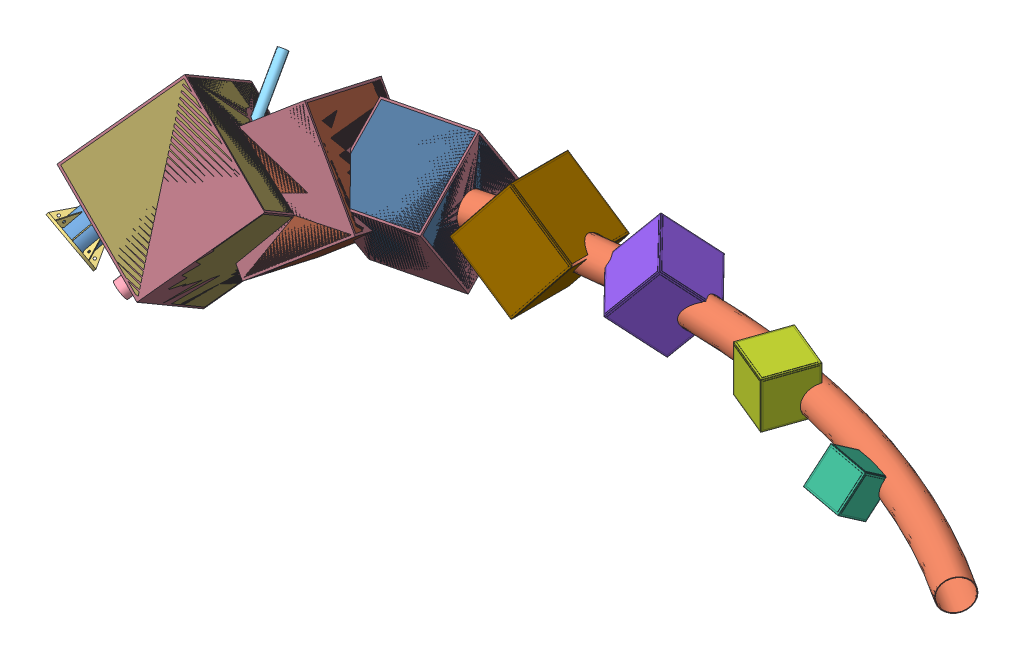
SolidWorks assembly tube1A, configuration Default. Lengths in mm.
Overall size (5509.57 1076.56 3983.87).
16 component instances, 13 part files, 11 mates.
Components (placement in the parent):
- tube1^tube1A-1: tube1^tube1A [A] at origin size (5509.57 567.54 3868.09) (virtual)
  - short-tube^tube1_tube1A-1: short-tube^tube1_tube1A [Default<As Machined>] at (-2066.9857 0 -335.3072) x (0.280011 0.524542 -0.804021) z (0.396988 0.699289 0.594471) size (592.32 168.28 168.28) (virtual)
  - tubes-1: tubes [tube1A] at origin size (5509.57 179.56 3868.09)
  - pipe_flange-1: pipe_flange [Default] at (-2222.5526 -291.4219 111.3861) x (0.228255 0.777129 0.58649) z (0.280011 0.524542 -0.804021) size (279.4 279.4 111.05)
-  tube1-support-arm^tube1A-1:  tube1-support-arm^tube1A [Default] at (-1841.3383 3296.5765 733.9451) x (0.486192 -0.007064 0.873823) z (0.120148 -0.98993 -0.074853) size (412.01 1066.18 424.01) (virtual)
- SpeakerArm^tube1A-1: SpeakerArm^tube1A [Default<As Machined>] at origin size (176.41 409.78 391.58) (virtual)
- cube_21-2: cube_21 [Default] at (1288.2494 29.6746 -537.6975) x (0.984604 -0.16863 0.046022) z (-0.163622 -0.79651 0.582065) size (201.3 201.3 201.3)
- cube_22-2: cube_22 [Default] at (645.1566 57.3606 -803.1505) x (0.933595 -0.053544 0.354308) z (-0.041789 -0.998295 -0.040754) size (257.18 257.18 257.18)
- cube_23-2: cube_23 [Default] at (-109.9957 38.0914 -951.4494) x (0.687918 -0.154019 0.709258) z (-0.466636 0.654617 0.59475) size (324.08 323.21 324.08)
- cube_24-2: cube_24 [Default] at (-714.1695 -0.9056 -890.2015) x (0.799244 -0.59975 -0.038856) z (0.182734 0.180907 0.966375) size (396.88 396.88 396.88)
- cube_25-2: cube_25 [Default] at (-1245.7406 -40.6251 -805.9879) x (0.987297 0.085082 -0.134183) z (0.001435 0.839726 0.543009) size (473.08 473.08 473.08)
- cube_26-2: cube_26 [Default] at (-1667.5795 -86.266 -627.0985) x (0.64678 -0.746775 0.15493) z (0.176738 0.344365 0.92205) size (549.27 549.27 549.27)
- cube_27-2: cube_27 [Default] at (-1930.8361 -95.1108 -262.0838) x (0.829782 -0.539124 0.144244) z (0.225274 0.560033 0.797254) size (622.94 622.94 622.94)
- boundry_cube-1: boundry_cube [cube25] at (-1245.7406 -40.6251 -805.9879) x (0.987297 0.085082 -0.134183) z (0.158877 -0.536304 0.828937) size (473.08 473.08 473.08) (hidden)
- boundry_cube-2: boundry_cube [cube26] at (-1667.5795 -86.266 -627.0985) x (0.741916 0.568981 -0.354712) z (0.176738 0.344365 0.92205) size (549.27 549.27 549.27) (hidden)
- boundry_cube-3: boundry_cube [cube27] at (-1930.8361 -95.1108 -262.0838) x (0.510601 0.629053 -0.586156) z (0.225274 0.560033 0.797254) size (622.94 622.94 622.94) (hidden)
Mates (geometry in assembly coordinates):
- Coincident24: coincident aligned: plane of cube_25-2 through (-1061.0829 -83.8847 -1154.7184) normal (-0.158877 0.536304 -0.828937); plane of boundry_cube-1 through (-1050.1275 -92.2707 -1162.2437) normal (-0.158877 0.536304 -0.828937)
- Coincident27: coincident aligned: plane of cube_25-2 through (-976.7164 -330.6914 -773.2717) normal (0.987297 0.085082 -0.134183); plane of boundry_cube-1 through (-1049.4487 304.9826 -905.3599) normal (0.987297 0.085082 -0.134183)
- Coincident28: coincident aligned: plane of cube_26-2 through (-1696.2708 178.0184 -1006.1067) normal (-0.64678 0.746775 -0.15493); plane of boundry_cube-2 through (-1592.9126 369.6656 -513.8356) normal (-0.64678 0.746775 -0.15493)
- Coincident29: coincident aligned: plane of cube_26-2 through (-1339.9537 -217.5451 -926.6711) normal (0.741916 0.568981 -0.354712); plane of boundry_cube-2 through (-1689.9903 180.5144 -1020.2947) normal (0.741916 0.568981 -0.354712)
- Coincident30: coincident aligned: plane of cube_26-2 through (-1253.0846 -38.5435 -426.5166) normal (0.176738 0.344365 0.92205); plane of boundry_cube-2 through (-1237.6527 -40.5192 -428.7367) normal (0.176738 0.344365 0.92205)
- Coincident32: coincident aligned: plane of cube_27-2 through (-2103.587 93.5395 -722.5254) normal (-0.829782 0.539124 -0.144244); plane of boundry_cube-3 through (-1960.0852 443.1707 -241.2609) normal (-0.829782 0.539124 -0.144244)
- Coincident33: coincident aligned: plane of cube_27-2 through (-1590.2335 -229.3186 -640.7874) normal (0.510601 0.629053 -0.586156); plane of boundry_cube-3 through (-2100.4163 94.3065 -737.8985) normal (0.510601 0.629053 -0.586156)
- Coincident34: coincident aligned: plane of cube_27-2 through (-1458.0798 106.3319 -146.4956) normal (0.225274 0.560033 0.797254); plane of boundry_cube-3 through (-1443.1848 107.3312 -151.4063) normal (0.225274 0.560033 0.797254)
- Coincident35: coincident aligned: plane of cube_25-2 through (-1058.6545 298.0775 -894.6572) normal (0.001435 0.839726 0.543009); plane of boundry_cube-1 through (-974.288 51.2708 -513.2105) normal (0.001435 0.839726 0.543009)
- PLANE1: unknown = 622.935 mm: point of  tube1-support-arm^tube1A-1; line of  tube1-support-arm^tube1A-1 through (-1398.3111 1.0472 -597.9764) axis (-0.723666 -0.201431 0.660101); face of  tube1-support-arm^tube1A-1; unknown of ?; unknown of ?; unknown of ?; unknown of ?; unknown of ?; unknown of ?; unknown of ?; unknown of ?; unknown of ?; unknown of ?; unknown of ?; unknown of ?; unknown of boundry_cube-2; unknown of boundry_cube-2; unknown of boundry_cube-2; unknown of boundry_cube-2
- cut27: unknown = 25.4 mm: line of boundry_cube-3 through (-2278.1562 51.3115 123.8764) axis (0.829782 -0.539124 0.144244); edge_curve of tube1^tube1A-1/short-tube^tube1_tube1A-1; edge_curve of  tube1-support-arm^tube1A-1; unknown of cube_27-2; unknown of cube_26-2; unknown of ?; unknown of ?; unknown of ?
